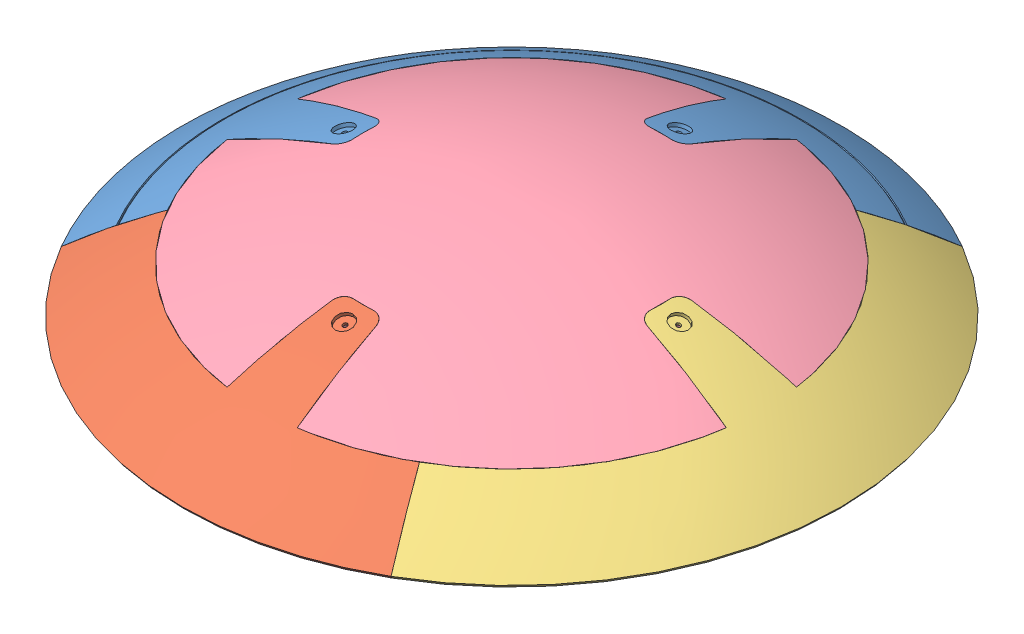
SolidWorks assembly BB-8Panel, configuration Default. Lengths in mm.
Overall size (286.79 250 286.79).
4 component instances, 4 part files, 6 mates.
Components (placement in the parent):
- BB-8Shell1-1: BB-8Shell1 [Default] at (74.6203 -96.0057 213.0674) size (215.09 38.2 215.09)
- BB-8Shell4-1: BB-8Shell4 [Default] at (74.6203 -96.0057 213.0674) x (0 0 -1) z (1 0 0) size (89.69 38.2 195.88)
- BB-8Shell5-1: BB-8Shell5 [Default] at (74.6203 -96.0057 213.0674) x (-1 0 0) z (0 0 -1) size (89.69 38.2 248.37)
- BB-8Shell6-1: BB-8Shell6 [Default] at (74.6203 -96.0057 213.0674) size (224.59 250 224.59)
Mates (geometry in assembly coordinates):
- Coincident2: coincident aligned: circle of BB-8Shell1-1; circle of BB-8Shell6-1
- Coincident3: coincident aligned: circle of BB-8Shell5-1; circle of BB-8Shell6-1
- Coincident4: coincident aligned: circle of BB-8Shell4-1; circle of BB-8Shell6-1
- Coincident5: coincident aligned: circle of BB-8Shell4-1; circle of BB-8Shell6-1
- Coincident6: coincident aligned: circle of BB-8Shell5-1; circle of BB-8Shell6-1
- Coincident7: coincident aligned: circle of BB-8Shell1-1; circle of BB-8Shell6-1
